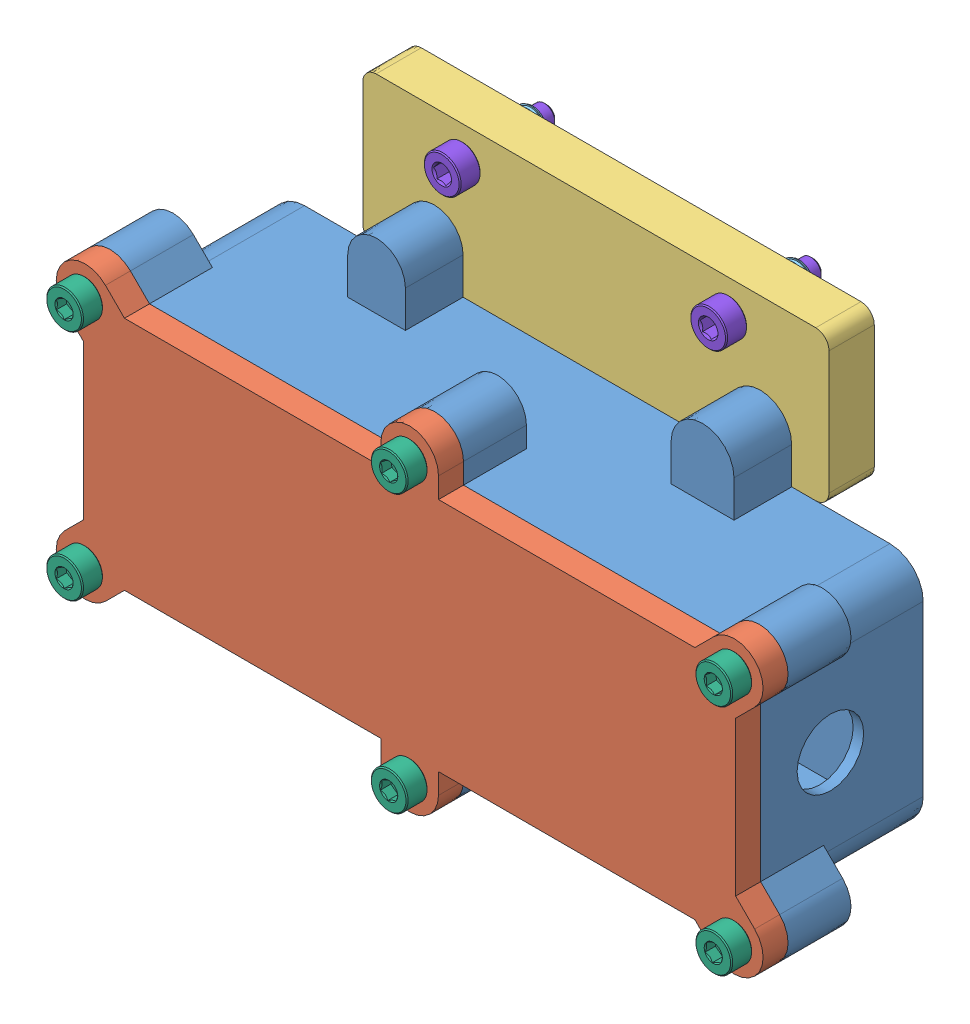
SolidWorks assembly EL-A0107-AA-HVI Assembly1, configuration Default. Lengths in mm.
Overall size (134.78 82.91 55.94).
30 component instances, 9 part files, 50 mates.
Components (placement in the parent):
- EL-50090-AA-HVI Enclosure1-1: EL-50090-AA-HVI Enclosure1 [Default] at (62.15 22.4625 5) size (134.78 67.33 31)
- EL-80091-AA-HVI PCB1-1: EL-80091-AA-HVI PCB1 [Default] at (128.7615 -37.799 12.4115) x (0 1 0) z (0 0 1) size (31.42 97.92 12)
- EL-60092-AA-HVI Enclosure Lid1-1: EL-60092-AA-HVI Enclosure Lid1 [Default] at (-49.5888 88.2769 31) size (134.78 63.74 4.76)
- EL-50093-AA-HVI Mounting Adapter1-1: EL-50093-AA-HVI Mounting Adapter1 [Default] at (0 44.925 0) size (88.9 28.57 8.62)
- AC-Heat Set Insert, M4x7-4.7 (94180A351)1-1: AC-Heat Set Insert, M4x7-4.7 (94180A351)1 [94180A351] at (0.2622 0.2622 28.65) size (6.35 6.35 4.7)
- AC-Heat Set Insert, M4x7-4.7 (94180A351)1-5: AC-Heat Set Insert, M4x7-4.7 (94180A351)1 [94180A351] at (62.15 -3.9097 28.65) x (-0.587416 -0.809285 0) z (0 0 1) size (6.35 6.35 4.7)
- AC-Heat Set Insert, M4x7-4.7 (94180A351)1-7: AC-Heat Set Insert, M4x7-4.7 (94180A351)1 [94180A351] at (124.0378 0.2622 28.65) x (-0.503998 -0.863705 0) z (0 0 1) size (6.35 6.35 4.7)
- FS-Heat Set Insert, M4x7-4.7 (94180A351)-7: FS-Heat Set Insert, M4x7-4.7 (94180A351) [94180A351] at (93.225 51.925 2.35) x (-0.503998 0.863705 0) z (0 0 -1) size (6.35 6.35 4.7)
- BR-Black Oxide C12.9 SHCS, M4x0.7-8 (91290A140)1-7: BR-Black Oxide C12.9 SHCS, M4x0.7-8 (91290A140)1 [91290A140] at (93.225 51.925 -1.62) x (0.720828 -0.693114 0) z (0 0 -1) size (7 7 12.17)
- FS-Heat Set Insert, M4x7-4.7 (94180A351)-11: FS-Heat Set Insert, M4x7-4.7 (94180A351) [94180A351] at (17.6365 32.94 9.65) size (6.35 6.35 4.7)
- FS-Heat Set Insert, M4x7-4.7 (94180A351)-12: FS-Heat Set Insert, M4x7-4.7 (94180A351) [94180A351] at (17.6365 11.985 9.65) size (6.35 6.35 4.7)
- FS-Heat Set Insert, M4x7-4.7 (94180A351)-13: FS-Heat Set Insert, M4x7-4.7 (94180A351) [94180A351] at (106.2765 22.365 9.65) size (6.35 6.35 4.7)
- BR-Black Oxide C12.9 SHCS, M4x0.7-5 (91290A138)1-1: BR-Black Oxide C12.9 SHCS, M4x0.7-5 (91290A138)1 [91290A138] at (17.6365 32.94 11.9115) x (-0.76758 0.640953 0) z (0 0 1) size (7 7 9.17)
- BR-Black Oxide C12.9 SHCS, M4x0.7-5 (91290A138)1-2: BR-Black Oxide C12.9 SHCS, M4x0.7-5 (91290A138)1 [91290A138] at (17.6365 11.985 11.9115) x (0.49038 0.871509 0) z (0 0 1) size (7 7 9.17)
- BR-Black Oxide C12.9 SHCS, M4x0.7-5 (91290A138)1-3: BR-Black Oxide C12.9 SHCS, M4x0.7-5 (91290A138)1 [91290A138] at (106.2765 22.365 11.9115) x (-0.851115 -0.52498 0) z (0 0 1) size (7 7 9.17) (hidden)
- 91290A154_Alloy Steel Socket Head Screw, M4x0.7, 16mm1-1: 91290A154_Alloy Steel Socket Head Screw, M4x0.7, 16mm1 [91290A154] at (36.5 67.15 -6) x (0.781191 -0.624293 0) z (0 0 1) size (7 7 20.04)
- 91290A154_Alloy Steel Socket Head Screw, M4x0.7, 16mm1-2: 91290A154_Alloy Steel Socket Head Screw, M4x0.7, 16mm1 [91290A154] at (87.3 67.15 -6) x (0.964834 0.262859 0) z (0 0 1) size (7 7 20.04)
- FS-Heat Set Insert, M4x7-4.7 (94180A351)-14: FS-Heat Set Insert, M4x7-4.7 (94180A351) [94180A351] at (36.5 67.15 -10.97) x (-0.244903 0.969548 0) z (0 0 1) size (6.35 6.35 4.7)
- FS-Heat Set Insert, M4x7-4.7 (94180A351)-15: FS-Heat Set Insert, M4x7-4.7 (94180A351) [94180A351] at (87.3 67.15 -10.97) x (0.839545 -0.543291 0) z (0 0 1) size (6.35 6.35 4.7)
- BR-Black Oxide C12.9 SHCS, M4x0.7-8 (91290A140)1-9: BR-Black Oxide C12.9 SHCS, M4x0.7-8 (91290A140)1 [91290A140] at (0.2622 0.2622 33.7625) size (7 7 12.17)
- BR-Black Oxide C12.9 SHCS, M4x0.7-8 (91290A140)1-10: BR-Black Oxide C12.9 SHCS, M4x0.7-8 (91290A140)1 [91290A140] at (62.15 -3.9097 33.7625) x (-0.596658 -0.802496 0) z (0 0 1) size (7 7 12.17)
- BR-Black Oxide C12.9 SHCS, M4x0.7-8 (91290A140)1-11: BR-Black Oxide C12.9 SHCS, M4x0.7-8 (91290A140)1 [91290A140] at (124.0378 0.2622 33.7625) x (-0.596658 -0.802496 0) z (0 0 1) size (7 7 12.17)
- AC-Heat Set Insert, M4x7-4.7 (94180A351)1-8: AC-Heat Set Insert, M4x7-4.7 (94180A351)1 [94180A351] at (0.2622 44.6628 28.65) x (1 0 0) z (0 0 -1) size (6.35 6.35 4.7)
- AC-Heat Set Insert, M4x7-4.7 (94180A351)1-9: AC-Heat Set Insert, M4x7-4.7 (94180A351)1 [94180A351] at (62.15 48.8347 28.65) x (-0.587416 0.809285 0) z (0 0 -1) size (6.35 6.35 4.7)
- AC-Heat Set Insert, M4x7-4.7 (94180A351)1-10: AC-Heat Set Insert, M4x7-4.7 (94180A351)1 [94180A351] at (124.0378 44.6628 28.65) x (-0.503998 0.863705 0) z (0 0 -1) size (6.35 6.35 4.7)
- BR-Black Oxide C12.9 SHCS, M4x0.7-8 (91290A140)1-8: BR-Black Oxide C12.9 SHCS, M4x0.7-8 (91290A140)1 [91290A140] at (31.075 51.925 -1.62) x (0.720828 -0.693114 0) z (0 0 -1) size (7 7 12.17)
- FS-Heat Set Insert, M4x7-4.7 (94180A351)-9: FS-Heat Set Insert, M4x7-4.7 (94180A351) [94180A351] at (31.075 51.925 2.35) x (-0.503998 0.863705 0) z (0 0 -1) size (6.35 6.35 4.7)
- BR-Black Oxide C12.9 SHCS, M4x0.7-8 (91290A140)1-12: BR-Black Oxide C12.9 SHCS, M4x0.7-8 (91290A140)1 [91290A140] at (0.2622 44.6628 33.7625) x (-1 0 0) z (0 0 1) size (7 7 12.17)
- BR-Black Oxide C12.9 SHCS, M4x0.7-8 (91290A140)1-13: BR-Black Oxide C12.9 SHCS, M4x0.7-8 (91290A140)1 [91290A140] at (62.15 48.8347 33.7625) x (0.596658 -0.802496 0) z (0 0 1) size (7 7 12.17)
- BR-Black Oxide C12.9 SHCS, M4x0.7-8 (91290A140)1-14: BR-Black Oxide C12.9 SHCS, M4x0.7-8 (91290A140)1 [91290A140] at (124.0378 44.6628 33.7625) x (0.596658 -0.802496 0) z (0 0 1) size (7 7 12.17)
Mates (geometry in assembly coordinates):
- Coincident1: coincident anti-aligned: plane of EL-500XX-AA-HVI Enclosure-1 through (62.15 22.4625 0) normal (0 0 -1)
- Coincident2: coincident anti-aligned: plane of EL-500XX-AA-HVI Enclosure-1 through (5 0 31) normal (0 -1 0)
- Coincident3: coincident anti-aligned: plane of EL-500XX-AA-HVI Enclosure-1 through (0 39.925 31) normal (-1 0 0)
- Width3: width aligned: plane of EL-500XX-AA-HVI Enclosure-1 through (5 39.925 31) normal (0 -1 0); plane of EL-800XX-BA-HVI Board-1 through (5 5 31) normal (0 1 0); plane of EL-500XX-AA-HVI Enclosure-1 through (13.1915 8.302 12) normal (0 -1 0); plane of EL-800XX-BA-HVI Board-1 through (111.1085 36.623 12) normal (0 1 0)
- Coincident5: coincident anti-aligned: plane of EL-500XX-AA-HVI Enclosure-1 through (17.6365 11.985 12) normal (0 0 1); plane of EL-800XX-BA-HVI Board-1 through (62.15 22.4625 12) normal (0 0 -1)
- Width4: width aligned: plane of EL-800XX-BA-HVI Board-1 through (111.1085 8.302 12) normal (1 0 0); plane of EL-500XX-AA-HVI Enclosure-1 through (13.1915 36.623 12) normal (-1 0 0); plane of EL-800XX-BA-HVI Board-1 through (5 39.925 31) normal (1 0 0); plane of EL-500XX-AA-HVI Enclosure-1 through (119.3 39.925 31) normal (-1 0 0)
- Coincident6: coincident aligned: plane of EL-500XX-AA-HVI Enclosure-1 through (62.15 22.4625 31) normal (0 0 1); plane of EL-60092-AA-HVI Enclosure Lid-1 through (-49.5888 88.2769 31) normal (0 0 1)
- Concentric2: concentric anti-aligned: cylinder of EL-500XX-AA-HVI Enclosure-1 through (31.075 51.925 9) axis (0 0 -1) radius 3.025; cylinder of EL-300XX-AA-HVI Enclosure Tab-2 through (31.075 51.925 0) axis (0 0 1) radius 2.25
- Coincident10: coincident anti-aligned: plane of EL-500XX-AA-HVI Enclosure-1 through (62.15 22.4625 0) normal (0 0 -1); plane of EL-300XX-AA-HVI Enclosure Tab-2 through (31.075 51.925 0) normal (0 0 1)
- Concentric4: concentric aligned: cylinder of EL-500XX-AA-HVI Enclosure-1 through (0.2622 0.2622 22) axis (0 0 1) radius 3.025; cylinder of FS-Heat Set Insert, M4x7-4.7 (94180A351)-1 through (0.2622 0.2622 31) axis (0 0 1) radius 2
- Coincident15: coincident aligned: plane of EL-500XX-AA-HVI Enclosure-1 through (62.15 22.4625 31) normal (0 0 1); plane of FS-Heat Set Insert, M4x7-4.7 (94180A351)-1 through (0.2622 2.2622 31) normal (0 0 1)
- Concentric6: concentric aligned: cylinder of EL-500XX-AA-HVI Enclosure-1 through (62.15 -3.9097 22) axis (0 0 1) radius 3.025; cylinder of AC-Heat Set Insert, M4x7-4.7 (94180A351)-5 through (62.15 -3.9097 31) axis (0 0 1) radius 2
- Coincident16: coincident aligned: plane of EL-500XX-AA-HVI Enclosure-1 through (62.15 22.4625 31) normal (0 0 1); plane of AC-Heat Set Insert, M4x7-4.7 (94180A351)-5 through (63.7686 -5.0845 31) normal (0 0 1)
- Concentric7: concentric aligned: cylinder of EL-500XX-AA-HVI Enclosure-1 through (124.0378 0.2622 22) axis (0 0 1) radius 3.025; cylinder of FS-Heat Set Insert, M4x7-4.7 (94180A351)-3 through (124.0378 0.2622 31) axis (0 0 1) radius 2
- Coincident17: coincident aligned: plane of EL-500XX-AA-HVI Enclosure-1 through (62.15 22.4625 31) normal (0 0 1); plane of FS-Heat Set Insert, M4x7-4.7 (94180A351)-3 through (125.7652 -0.7458 31) normal (0 0 1)
- Concentric16: concentric aligned: cylinder of EL-500XX-AA-HVI Enclosure-1 through (93.225 51.925 9) axis (0 0 -1) radius 3.025; cylinder of FS-Heat Set Insert, M4x7-4.7 (94180A351)-7 through (93.225 51.925 0) axis (0 0 -1) radius 2
- Coincident21: coincident aligned: plane of EL-500XX-AA-HVI Enclosure-1 through (62.15 22.4625 0) normal (0 0 -1); plane of FS-Heat Set Insert, M4x7-4.7 (94180A351)-7 through (94.9524 52.933 0) normal (0 0 -1)
- Concentric17: concentric anti-aligned: cylinder of FS-Heat Set Insert, M4x7-4.7 (94180A351)-7 through (93.225 51.925 0) axis (0 0 -1) radius 2; cylinder of BR-Black Oxide C12.9 SHCS, M4x0.7-8 (91290A140)-7 through (93.225 51.925 4.38) axis (0 0 1) radius 2
- Concentric19: concentric anti-aligned: cylinder of EL-500XX-AA-HVI Enclosure-1 through (17.6365 32.94 12) axis (0 0 -1) radius 3.025; cylinder of FS-Heat Set Insert, M4x7-4.7 (94180A351)-11 through (17.6365 32.94 12) axis (0 0 1) radius 2
- Coincident25: coincident aligned: plane of EL-500XX-AA-HVI Enclosure-1 through (17.6365 32.94 12) normal (0 0 1); plane of FS-Heat Set Insert, M4x7-4.7 (94180A351)-11 through (17.6365 34.94 12) normal (0 0 1)
- Concentric21: concentric anti-aligned: cylinder of EL-500XX-AA-HVI Enclosure-1 through (17.6365 11.985 12) axis (0 0 -1) radius 3.025; cylinder of FS-Heat Set Insert, M4x7-4.7 (94180A351)-12 through (17.6365 11.985 12) axis (0 0 1) radius 2
- Coincident26: coincident aligned: plane of EL-500XX-AA-HVI Enclosure-1 through (17.6365 11.985 12) normal (0 0 1); plane of FS-Heat Set Insert, M4x7-4.7 (94180A351)-12 through (17.6365 13.985 12) normal (0 0 1)
- Concentric22: concentric anti-aligned: cylinder of EL-500XX-AA-HVI Enclosure-1 through (106.2765 22.365 12) axis (0 0 -1) radius 3.025; cylinder of FS-Heat Set Insert, M4x7-4.7 (94180A351)-13 through (106.2765 22.365 12) axis (0 0 1) radius 2
- Coincident28: coincident aligned: plane of EL-500XX-AA-HVI Enclosure-1 through (106.2765 22.365 12) normal (0 0 1); plane of FS-Heat Set Insert, M4x7-4.7 (94180A351)-13 through (106.2765 24.365 12) normal (0 0 1)
- Concentric23: concentric anti-aligned: cylinder of FS-Heat Set Insert, M4x7-4.7 (94180A351)-11 through (17.6365 32.94 12) axis (0 0 1) radius 2; cylinder of BR-Black Oxide C12.9 SHCS, M4x0.7-5 (91290A138)-1 through (17.6365 32.94 7.4115) axis (0 0 -1) radius 2
- Coincident29: coincident anti-aligned: plane of EL-800XX-BA-HVI Board-1 through (62.15 22.4625 12.4115) normal (0 0 1); plane of BR-Black Oxide C12.9 SHCS, M4x0.7-5 (91290A138)-1 through (15.5214 30.407 12.4115) normal (0 0 -1)
- Concentric25: concentric anti-aligned: cylinder of FS-Heat Set Insert, M4x7-4.7 (94180A351)-12 through (17.6365 11.985 12) axis (0 0 1) radius 2; cylinder of BR-Black Oxide C12.9 SHCS, M4x0.7-5 (91290A138)-2 through (17.6365 11.985 7.4115) axis (0 0 -1) radius 2
- Coincident30: coincident anti-aligned: plane of EL-800XX-BA-HVI Board-1 through (62.15 22.4625 12.4115) normal (0 0 1); plane of BR-Black Oxide C12.9 SHCS, M4x0.7-5 (91290A138)-2 through (14.7605 13.6033 12.4115) normal (0 0 -1)
- Concentric26: concentric anti-aligned: cylinder of FS-Heat Set Insert, M4x7-4.7 (94180A351)-13 through (106.2765 22.365 12) axis (0 0 1) radius 2; cylinder of BR-Black Oxide C12.9 SHCS, M4x0.7-5 (91290A138)-3 through (106.2765 22.365 7.4115) axis (0 0 -1) radius 2
- Coincident32: coincident anti-aligned: plane of EL-800XX-BA-HVI Board-1 through (62.15 22.4625 12.4115) normal (0 0 1); plane of BR-Black Oxide C12.9 SHCS, M4x0.7-5 (91290A138)-3 through (108.0089 19.5563 12.4115) normal (0 0 -1)
- Coincident33: coincident anti-aligned: plane of EL-500XX-AA-HVI Enclosure-1 through (62.15 22.4625 0) normal (0 0 -1); plane of EL-50093-AA-HVI Mounting Adapter-1 through (0 44.925 0) normal (0 0 1)
- Coincident34: coincident aligned: plane of EL-500XX-AA-HVI Enclosure-1 through (5 44.925 31) normal (0 1 0); plane of EL-50093-AA-HVI Mounting Adapter-1 through (0 44.925 0) normal (0 1 0)
- Coincident35: coincident anti-aligned: plane of EL-500XX-AA-HVI Enclosure-1 through (0 39.925 31) normal (-1 0 0); plane of EL-50093-AA-HVI Mounting Adapter-1 through (0 44.925 0) normal (1 0 0)
- Coincident36: coincident anti-aligned: plane of EL-50093-AA-HVI Mounting Adapter-1 through (95.475 51.925 -3.62) normal (0 0 -1); plane of BR-Black Oxide C12.9 SHCS, M4x0.7-8 (91290A140)-7 through (90.9377 49.5463 -3.62) normal (0 0 1)
- Concentric28: concentric anti-aligned: cylinder of EL-50093-AA-HVI Mounting Adapter-1 through (36.5 67.15 0) axis (0 0 1) radius 2.25; cylinder of 91290A154_Alloy Steel Socket Head Screw, M4x0.7, 16mm-1 through (36.5 67.15 -16) axis (0 0 -1) radius 2
- Concentric29: concentric anti-aligned: cylinder of EL-50093-AA-HVI Mounting Adapter-1 through (87.3 67.15 0) axis (0 0 1) radius 2.25; cylinder of 91290A154_Alloy Steel Socket Head Screw, M4x0.7, 16mm-2 through (87.3 67.15 -16) axis (0 0 -1) radius 2
- Coincident37: coincident anti-aligned: plane of EL-50093-AA-HVI Mounting Adapter-1 through (0 44.925 0) normal (0 0 1); plane of 91290A154_Alloy Steel Socket Head Screw, M4x0.7, 16mm-1 through (38.5602 69.7279 0) normal (0 0 -1)
- Coincident38: coincident anti-aligned: plane of EL-50093-AA-HVI Mounting Adapter-1 through (0 44.925 0) normal (0 0 1); plane of 91290A154_Alloy Steel Socket Head Screw, M4x0.7, 16mm-2 through (86.4326 70.334 0) normal (0 0 -1)
- Concentric30: concentric anti-aligned: cylinder of 91290A154_Alloy Steel Socket Head Screw, M4x0.7, 16mm-2 through (87.3 67.15 -16) axis (0 0 -1) radius 2; cylinder of FS-Heat Set Insert, M4x7-4.7 (94180A351)-15 through (87.3 67.15 -8.62) axis (0 0 1) radius 2
- Coincident39: coincident anti-aligned: plane of EL-50093-AA-HVI Mounting Adapter-1 through (0 44.925 -8.62) normal (0 0 -1); plane of FS-Heat Set Insert, M4x7-4.7 (94180A351)-15 through (88.3866 68.8291 -8.62) normal (0 0 1)
- Concentric31: concentric anti-aligned: cylinder of 91290A154_Alloy Steel Socket Head Screw, M4x0.7, 16mm-1 through (36.5 67.15 -16) axis (0 0 -1) radius 2; cylinder of FS-Heat Set Insert, M4x7-4.7 (94180A351)-14 through (36.5 67.15 -8.62) axis (0 0 1) radius 2
- Coincident40: coincident anti-aligned: plane of EL-50093-AA-HVI Mounting Adapter-1 through (0 44.925 -8.62) normal (0 0 -1); circle of FS-Heat Set Insert, M4x7-4.7 (94180A351)-14
- Coincident41: coincident aligned: plane of EL-50090-AA-HVI Enclosure-1 through (0 39.925 31) normal (-1 0 0); plane of EL-600XX-AA-HVI Enclosure Lid-1 through (0 37.1468 35.7625) normal (-1 0 0)
- Coincident42: coincident aligned: plane of EL-50090-AA-HVI Enclosure-1 through (5 0 31) normal (0 -1 0); plane of EL-600XX-AA-HVI Enclosure Lid-1 through (7.7782 0 35.7625) normal (0 -1 0)
- Concentric32: concentric anti-aligned: cylinder of AC-Heat Set Insert, M4x7-4.7 (94180A351)-1 through (0.2622 0.2622 31) axis (0 0 1) radius 2; cylinder of BR-Black Oxide C12.9 SHCS, M4x0.7-8 (91290A140)-9 through (0.2622 0.2622 27.7625) axis (0 0 -1) radius 2
- Coincident43: coincident anti-aligned: plane of EL-60092-AA-HVI Enclosure Lid-1 through (62.15 48.8347 35.7625) normal (0 0 1); plane of BR-Black Oxide C12.9 SHCS, M4x0.7-8 (91290A140)-9 through (0.2622 3.5622 35.7625) normal (0 0 -1)
- Concentric33: concentric anti-aligned: cylinder of AC-Heat Set Insert, M4x7-4.7 (94180A351)-5 through (62.15 -3.9097 31) axis (0 0 1) radius 2; cylinder of BR-Black Oxide C12.9 SHCS, M4x0.7-8 (91290A140)-10 through (62.15 -3.9097 27.7625) axis (0 0 -1) radius 2
- Coincident45: coincident anti-aligned: plane of EL-60092-AA-HVI Enclosure Lid-1 through (62.15 48.8347 35.7625) normal (0 0 1); plane of BR-Black Oxide C12.9 SHCS, M4x0.7-8 (91290A140)-10 through (64.7982 -5.8787 35.7625) normal (0 0 -1)
- Concentric34: concentric anti-aligned: cylinder of EL-60092-AA-HVI Enclosure Lid-1 through (124.0378 0.2622 35.7625) axis (0 0 1) radius 2.25; cylinder of BR-Black Oxide C12.9 SHCS, M4x0.7-8 (91290A140)-11 through (124.0378 0.2622 27.7625) axis (0 0 -1) radius 2
- Coincident46: coincident anti-aligned: plane of EL-60092-AA-HVI Enclosure Lid-1 through (62.15 48.8347 35.7625) normal (0 0 1); circle of BR-Black Oxide C12.9 SHCS, M4x0.7-8 (91290A140)-11
